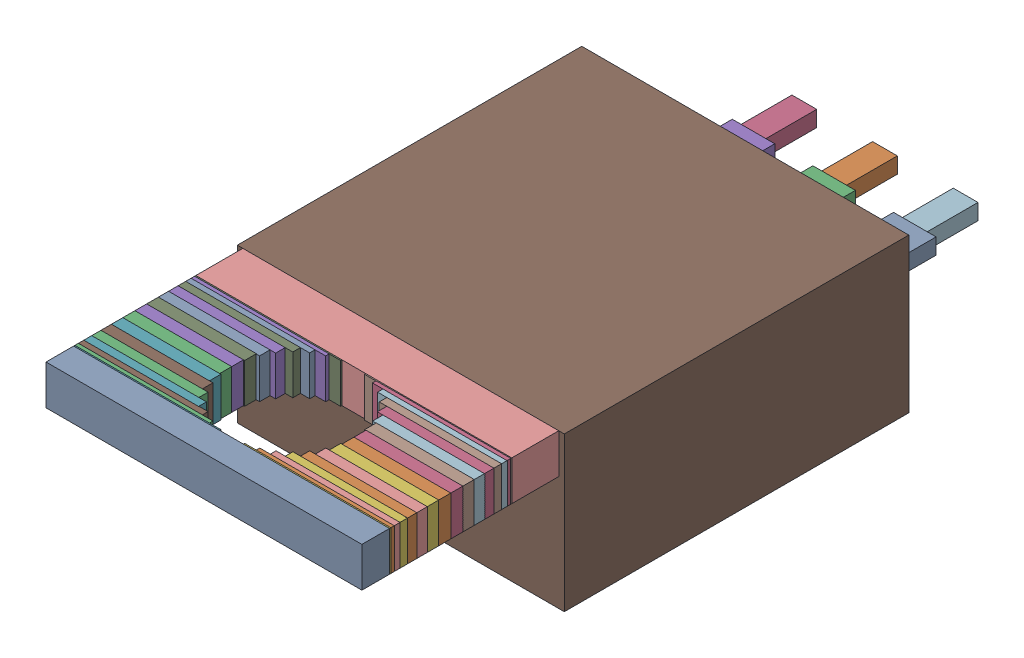
SolidWorks assembly Q2.step, configuration Default. Lengths in mm.
Overall size (10.3 4.85 21.45).
82 component instances, 18 part files, 0 mates.
Components (placement in the parent):
- 6138241504.step-1: 6138241504.step [Default] at (62.103 54.115 18.98) size (9.95 1.25 0.87)
  - Extruded-25.step-1: Extruded-25.step [Default] at origin size (9.95 1.25 0.87)
- 6138241344.step-1: 6138241344.step [Default] at (65.553 54.115 17.05) size (3.05 1.25 0.38)
  - Extruded-26.step-1: Extruded-26.step [Default] at origin size (3.05 1.25 0.38)
- 6138241344.step-2: 6138241344.step [Default] at (58.653 54.115 17.05) size (3.05 1.25 0.38)
  - Extruded-26.step-1: Extruded-26.step [Default] at origin size (3.05 1.25 0.38)
- 6138241104.step-1: 6138241104.step [Default] at (65.553 54.115 16.67) size (3.05 1.25 0.38)
  - Extruded-27.step-1: Extruded-27.step [Default] at origin size (3.05 1.25 0.38)
- 6138241104.step-2: 6138241104.step [Default] at (58.653 54.115 16.67) size (3.05 1.25 0.38)
  - Extruded-27.step-1: Extruded-27.step [Default] at origin size (3.05 1.25 0.38)
- 6138240864.step-1: 6138240864.step [Default] at (65.5345 54.115 17.43) size (3.09 1.25 0.36)
  - Extruded-28.step-1: Extruded-28.step [Default] at origin size (3.09 1.25 0.36)
- 6138240864.step-2: 6138240864.step [Default] at (58.6715 54.115 17.43) size (3.09 1.25 0.36)
  - Extruded-28.step-1: Extruded-28.step [Default] at origin size (3.09 1.25 0.36)
- 6138240624.step-1: 6138240624.step [Default] at (65.5345 54.115 16.31) size (3.09 1.25 0.37)
  - Extruded-29.step-1: Extruded-29.step [Default] at origin size (3.09 1.25 0.37)
- 6138240624.step-2: 6138240624.step [Default] at (58.6715 54.115 16.31) size (3.09 1.25 0.37)
  - Extruded-29.step-1: Extruded-29.step [Default] at origin size (3.09 1.25 0.37)
- 6138240384.step-1: 6138240384.step [Default] at (65.4797 54.115 17.79) size (3.2 1.25 0.33)
  - Extruded-30.step-1: Extruded-30.step [Default] at origin size (3.2 1.25 0.33)
- 6138240384.step-2: 6138240384.step [Default] at (58.7263 54.115 17.79) size (3.2 1.25 0.33)
  - Extruded-30.step-1: Extruded-30.step [Default] at origin size (3.2 1.25 0.33)
- 6138240144.step-1: 6138240144.step [Default] at (65.4797 54.115 15.98) size (3.2 1.25 0.34)
  - Extruded-31.step-1: Extruded-31.step [Default] at origin size (3.2 1.25 0.34)
- 6138240144.step-2: 6138240144.step [Default] at (58.7263 54.115 15.98) size (3.2 1.25 0.34)
  - Extruded-31.step-1: Extruded-31.step [Default] at origin size (3.2 1.25 0.34)
- 6138239904.step-1: 6138239904.step [Default] at (65.3908 54.115 18.12) size (3.37 1.25 0.3)
  - Extruded-32.step-1: Extruded-32.step [Default] at origin size (3.37 1.25 0.3)
- 6138239904.step-2: 6138239904.step [Default] at (58.8152 54.115 18.12) size (3.37 1.25 0.3)
  - Extruded-32.step-1: Extruded-32.step [Default] at origin size (3.37 1.25 0.3)
- 6138239904.step-3: 6138239904.step [Default] at (65.3908 54.115 15.69) size (3.37 1.25 0.3)
  - Extruded-32.step-1: Extruded-32.step [Default] at origin size (3.37 1.25 0.3)
- 6138239904.step-4: 6138239904.step [Default] at (58.8152 54.115 15.69) size (3.37 1.25 0.3)
  - Extruded-32.step-1: Extruded-32.step [Default] at origin size (3.37 1.25 0.3)
- 6138239504.step-1: 6138239504.step [Default] at (65.2711 54.115 18.41) size (3.61 1.25 0.25)
  - Extruded-33.step-1: Extruded-33.step [Default] at origin size (3.61 1.25 0.25)
- 6138239504.step-2: 6138239504.step [Default] at (58.9349 54.115 18.41) size (3.61 1.25 0.25)
  - Extruded-33.step-1: Extruded-33.step [Default] at origin size (3.61 1.25 0.25)
- 6138239264.step-1: 6138239264.step [Default] at (65.2711 54.115 15.45) size (3.61 1.25 0.24)
  - Extruded-34.step-1: Extruded-34.step [Default] at origin size (3.61 1.25 0.24)
- 6138239264.step-2: 6138239264.step [Default] at (58.9349 54.115 15.45) size (3.61 1.25 0.24)
  - Extruded-34.step-1: Extruded-34.step [Default] at origin size (3.61 1.25 0.24)
- 6138239024.step-1: 6138239024.step [Default] at (65.1252 54.115 18.65) size (3.91 1.25 0.18)
  - Extruded-35.step-1: Extruded-35.step [Default] at origin size (3.91 1.25 0.18)
- 6138239024.step-2: 6138239024.step [Default] at (59.0808 54.115 18.65) size (3.91 1.25 0.18)
  - Extruded-35.step-1: Extruded-35.step [Default] at origin size (3.91 1.25 0.18)
- 6138239024.step-3: 6138239024.step [Default] at (65.1252 54.115 15.27) size (3.91 1.25 0.18)
  - Extruded-35.step-1: Extruded-35.step [Default] at origin size (3.91 1.25 0.18)
- 6138239024.step-4: 6138239024.step [Default] at (59.0808 54.115 15.27) size (3.91 1.25 0.18)
  - Extruded-35.step-1: Extruded-35.step [Default] at origin size (3.91 1.25 0.18)
- 6138238624.step-1: 6138238624.step [Default] at (64.9588 54.115 18.83) size (4.24 1.25 0.11)
  - Extruded-36.step-1: Extruded-36.step [Default] at origin size (4.24 1.25 0.11)
- 6138238624.step-2: 6138238624.step [Default] at (59.2472 54.115 18.83) size (4.24 1.25 0.11)
  - Extruded-36.step-1: Extruded-36.step [Default] at origin size (4.24 1.25 0.11)
- 6138238384.step-1: 6138238384.step [Default] at (64.9588 54.115 15.16) size (4.24 1.25 0.12)
  - Extruded-37.step-1: Extruded-37.step [Default] at origin size (4.24 1.25 0.12)
- 6138238384.step-2: 6138238384.step [Default] at (59.2472 54.115 15.16) size (4.24 1.25 0.12)
  - Extruded-37.step-1: Extruded-37.step [Default] at origin size (4.24 1.25 0.12)
- 6138238144.step-1: 6138238144.step [Default] at (64.7783 54.115 18.94) size (4.6 1.25 0.04)
  - Extruded-38.step-1: Extruded-38.step [Default] at origin size (4.6 1.25 0.04)
- 6138238144.step-2: 6138238144.step [Default] at (59.4277 54.115 18.94) size (4.6 1.25 0.04)
  - Extruded-38.step-1: Extruded-38.step [Default] at origin size (4.6 1.25 0.04)
- 6138238144.step-3: 6138238144.step [Default] at (64.7783 54.115 15.13) size (4.6 1.25 0.04)
  - Extruded-38.step-1: Extruded-38.step [Default] at origin size (4.6 1.25 0.04)
- 6138238144.step-4: 6138238144.step [Default] at (59.4277 54.115 15.13) size (4.6 1.25 0.04)
  - Extruded-38.step-1: Extruded-38.step [Default] at origin size (4.6 1.25 0.04)
- 6138237744.step-1: 6138237744.step [Default] at (62.103 54.115 13.65) size (9.95 1.25 1.48)
  - Extruded-39.step-1: Extruded-39.step [Default] at origin size (9.95 1.25 1.48)
- 6138237584.step-1: 6138237584.step [Default] at (62.103 52.315 2.8) size (10.3 4.85 10.85)
  - Extruded-40.step-1: Extruded-40.step [Default] at origin size (10.3 4.85 10.85)
- 6138237424.step-1: 6138237424.step [Default] at (64.643 52.07 -1.6) size (0.78 0.5 1.6)
  - Extruded-41.step-1: Extruded-41.step [Default] at origin size (0.78 0.5 1.6)
- 6138237264.step-1: 6138237264.step [Default] at (64.643 52.07 0) size (1.34 0.5 2.8)
  - Extruded-42.step-1: Extruded-42.step [Default] at origin size (1.34 0.5 2.8)
- 6138237424.step-2: 6138237424.step [Default] at (62.103 52.07 -1.6) size (0.78 0.5 1.6)
  - Extruded-41.step-1: Extruded-41.step [Default] at origin size (0.78 0.5 1.6)
- 6138237264.step-2: 6138237264.step [Default] at (62.103 52.07 0) size (1.34 0.5 2.8)
  - Extruded-42.step-1: Extruded-42.step [Default] at origin size (1.34 0.5 2.8)
- 6138237424.step-3: 6138237424.step [Default] at (59.563 52.07 -1.6) size (0.78 0.5 1.6)
  - Extruded-41.step-1: Extruded-41.step [Default] at origin size (0.78 0.5 1.6)
- 6138237264.step-3: 6138237264.step [Default] at (59.563 52.07 0) size (1.34 0.5 2.8)
  - Extruded-42.step-1: Extruded-42.step [Default] at origin size (1.34 0.5 2.8)
